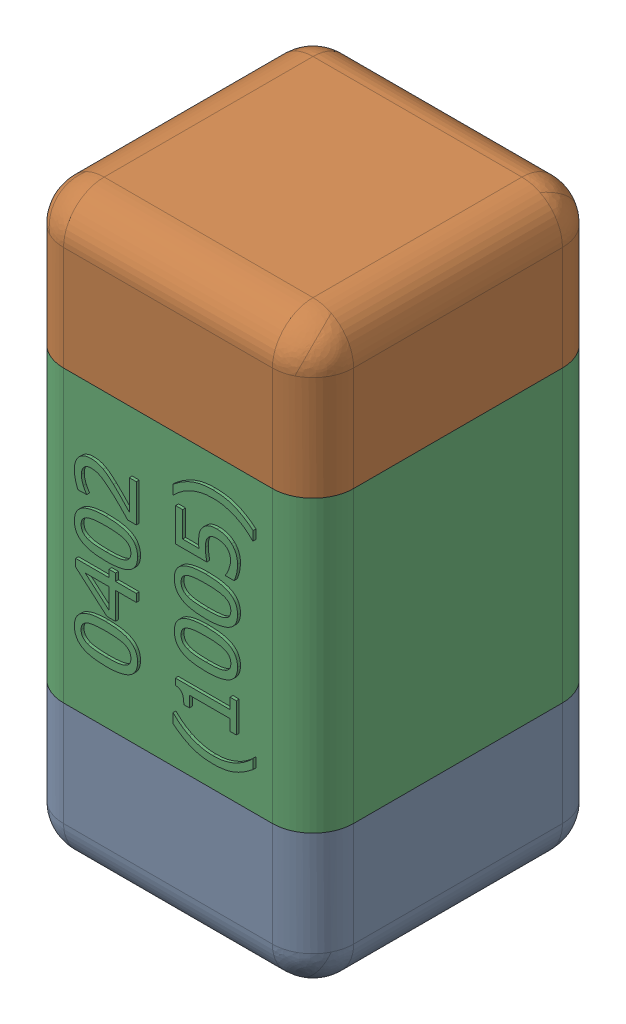
SolidWorks assembly C25, configuration Standard. Lengths in mm.
Overall size (0.51 1.01 0.51).
4 component instances, 3 part files, 0 mates.
Components (placement in the parent):
- C25-subassembly-1-1: C25-subassembly-1 [Standard] at (-15.3 -15.3999 0) x (0 1 0) z (0 0 1) size (1.01 0.51 0.51)
  - User Library-0402_Cap-1: User Library-0402_Cap [Standard] at origin size (0.26 0.51 0.51)
  - User Library-0402_Cap-1-1: User Library-0402_Cap-1 [Standard] at origin size (0.26 0.5 0.51)
  - User Library-0402_Cap-2-1: User Library-0402_Cap-2 [Standard] at origin size (0.5 0.5 0.51)
